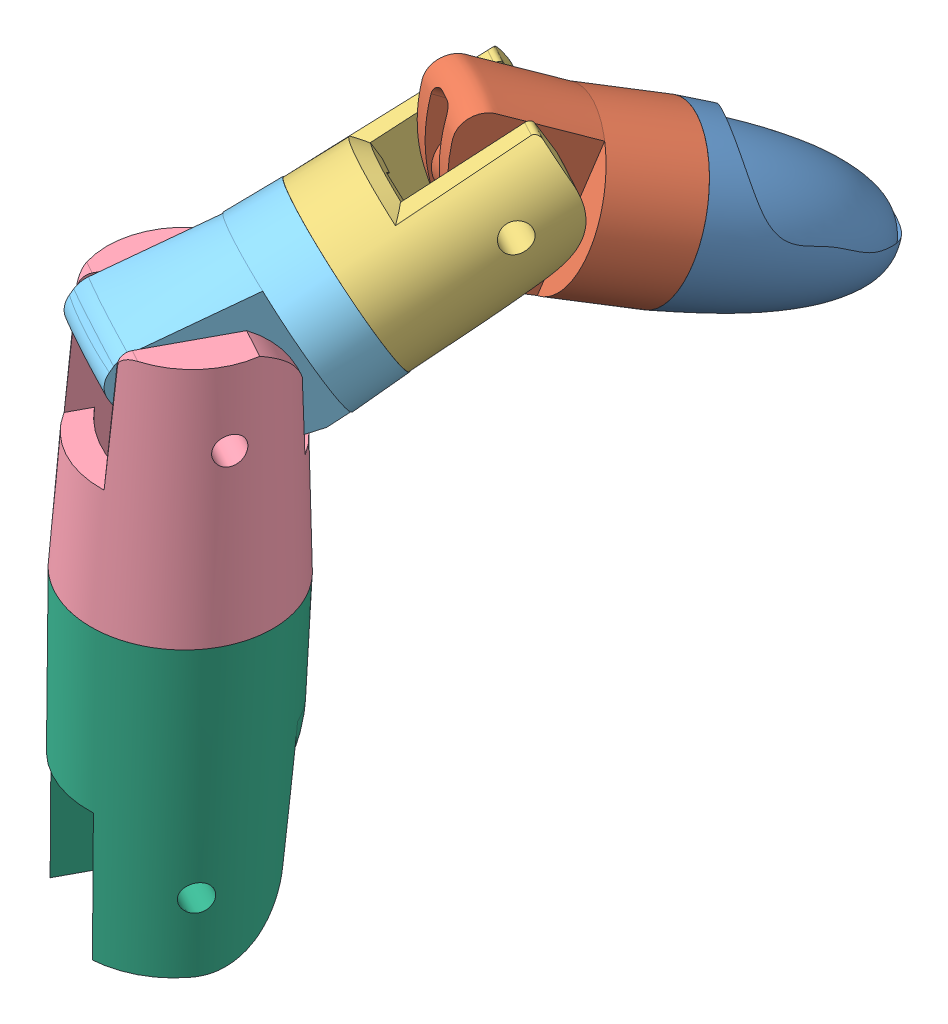
SolidWorks assembly parmak index 3 montaj, configuration Varsayılan. Lengths in mm.
Overall size (43.04 64.14 59.13).
6 component instances, 6 part files, 15 mates.
Components (placement in the parent):
- Parmak ucu index3-1: Parmak ucu index3 [Varsayılan] at (14.0361 -33.2074 -8.0627) x (0.886989 -0.046567 0.459437) z (0.200895 0.934735 -0.293107) size (14.01 17 14.01)
- Parmak index3-2-1: Parmak index3-2 [Varsayılan] at (14.0361 -33.2074 -8.0627) x (0.200895 0.934735 -0.293107) z (-0.415803 0.352281 0.838455) size (14.75 14.1 18.06)
- Parmak index3-6-1: Parmak index3-6 [Varsayılan] at (11.0263 -26.583 -1.5806) x (-0.421167 -0.489607 0.763481) z (0.18939 -0.870699 -0.453888) size (16 15.15 14.93)
- Parmak index3-3-1: Parmak index3-3 [Varsayılan] at (-1.6138 -56.0041 19.8405) x (-0.046567 -0.998851 -0.011338) z (-0.459437 0.011338 0.888138) size (22 17 17)
- Parmak index3-5-1: Parmak index3-5 [Varsayılan] at (4.2877 -34.4167 10.6351) x (-0.421167 -0.489607 0.763481) z (-0.886989 0.046567 -0.459437) size (17.47 16.52 15.41)
- Parmak index3-4-1: Parmak index3-4 [Varsayılan] at (-1.6138 -56.0041 19.8405) x (-0.886989 0.046567 -0.459437) z (-0.459437 0.011338 0.888138) size (17 27 17)
Mates (geometry in assembly coordinates):
- Coincident1: coincident anti-aligned: plane of Parmak ucu index3-1 through (12.1492 -39.4004 -5.0475) normal (-0.374601 0.509244 0.774819); plane of Parmak index3-2-1 through (13.4659 -35.2102 -7.1649) normal (0.374601 -0.509244 -0.774819)
- Concentric1: concentric aligned: circle of Parmak ucu index3-1; circle of Parmak index3-2-1
- Coincident2: coincident anti-aligned: plane of Parmak index3-2-1 through (11.9284 -27.4795 -10.4869) normal (-0.886989 0.046567 -0.459437); plane of Parmak index3-6-1 through (8.1436 -26.4317 -3.0738) normal (0.886989 -0.046567 0.459437)
- Concentric3: concentric aligned: cylinder of Parmak index3-2-1 through (14.9844 -28.4886 5.9297) axis (-0.886989 0.046567 -0.459437) radius 1.25; cylinder of Parmak index3-6-1 through (15.3835 -28.5096 6.1364) axis (-0.886989 0.046567 -0.459437) radius 1.25
- Coincident3: coincident anti-aligned: plane of Parmak index3-6-1 through (-17.7553 -26.8038 3.3573) normal (-0.421167 -0.489607 0.763481); plane of Parmak index3-5-1 through (4.2877 -34.4167 10.6351) normal (0.421167 0.489607 -0.763481)
- Concentric4: concentric anti-aligned: circle of Parmak index3-6-1; circle of Parmak index3-5-1
- Coincident6: coincident anti-aligned: plane of Parmak index3-3-1 through (-9.9779 -55.6928 26.7693) normal (0.886989 -0.046567 0.459437); plane of Parmak index3-5-1 through (-4.0429 -38.2142 17.0827) normal (-0.886989 0.046567 -0.459437)
- Concentric6: concentric aligned: cylinder of Parmak index3-3-1 through (8.1982 -41.193 24.1643) axis (-0.886989 0.046567 -0.459437) radius 1.25; cylinder of Parmak index3-5-1 through (6.1645 -41.0862 23.1109) axis (-0.886989 0.046567 -0.459437) radius 1.25
- Coincident8: coincident anti-aligned: plane of Parmak index3-3-1 through (-1.6138 -56.0041 19.8405) normal (-0.046567 -0.998851 -0.011338); plane of Parmak index3-4-1 through (-1.6138 -56.0041 19.8405) normal (0.046567 0.998851 0.011338)
- Concentric7: concentric anti-aligned: cone of Parmak index3-3-1 through (-0.5894 -34.0294 20.0899) axis (0.046567 0.998851 0.011338); cone of Parmak index3-4-1 through (-1.6138 -56.0041 19.8405) axis (-0.046567 -0.998851 -0.011338)
- Coincident9: coincident aligned: plane of Parmak index3-3-1 through (-1.6138 -56.0041 19.8405) normal (-0.459437 0.011338 0.888138); plane of Parmak index3-4-1 through (-1.6138 -56.0041 19.8405) normal (-0.459437 0.011338 0.888138)
- Coincident10: coincident anti-aligned: plane of Parmak index3-6-1 through (11.0263 -26.583 -1.5806) normal (0.18939 -0.870699 -0.453888); plane of Parmak index3-5-1
- Coincident11: coincident aligned: plane of Parmak ucu index3-1 through (13.4659 -35.2102 -7.1649) normal (0.270046 0.859361 -0.43425); plane of Parmak index3-2-1
- LimitAngle4: limit planar angle = 2.094395 rad aligned: plane of Parmak index3-3-1 through (-1.6138 -56.0041 19.8405) normal (-0.459437 0.011338 0.888138); plane of Parmak index3-6-1 through (11.0263 -26.583 -1.5806) normal (0.18939 -0.870699 -0.453888)
- LimitAngle7: limit planar angle = 4.014257 rad aligned: plane of Parmak index3-2-1; plane of Parmak index3-6-1 through (11.0263 -26.583 -1.5806) normal (0.18939 -0.870699 -0.453888)
